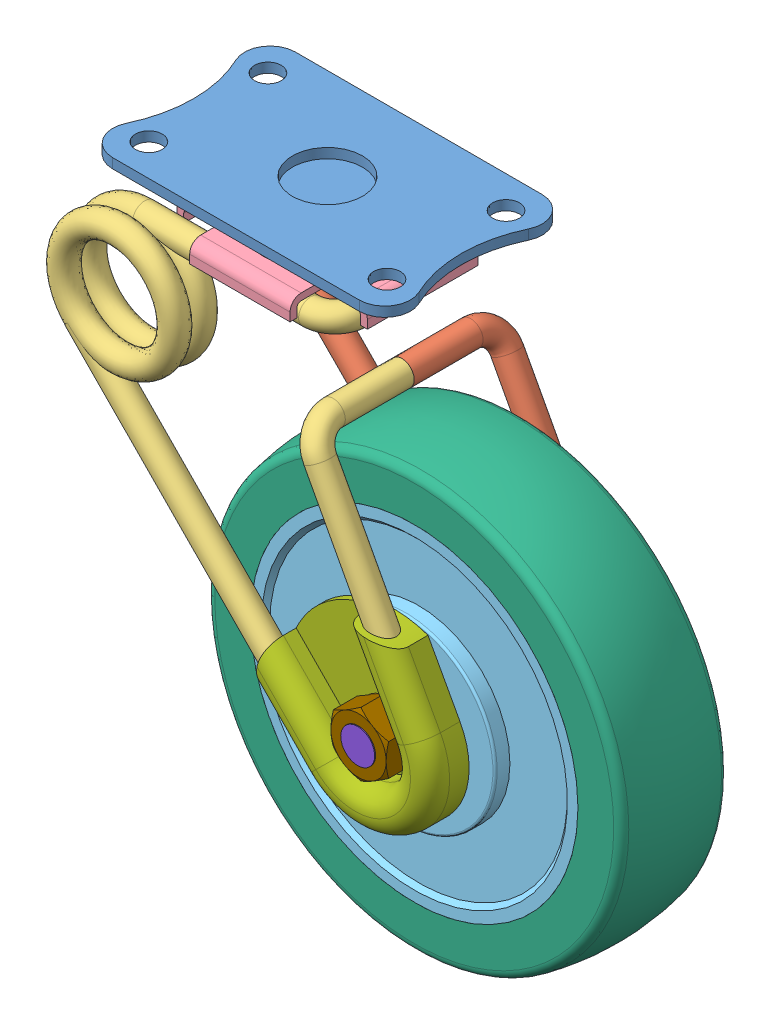
SolidWorks assembly SUSAJ-TS6-100, configuration ﾃﾞﾌｫﾙﾄ. Lengths in mm.
Overall size (125.88 136.72 53.61).
12 component instances, 9 part files, 17 mates.
Components (placement in the parent):
- table1-1: table1 [ﾃﾞﾌｫﾙﾄ] at (4.6677 7.0382 70) size (70 6.3 43)
- spring-1: spring [ﾃﾞﾌｫﾙﾄ] at (-22.2933 -17.0618 54) x (1 0 0) z (0 1 0) size (91.52 25.65 92.48)
- spring_mirror-1: spring_mirror [ﾃﾞﾌｫﾙﾄ] at (-22.2933 -17.0618 54) x (1 0 0) z (0 1 0) size (91.42 25.65 92.38)
- table2-1: table2 [ﾃﾞﾌｫﾙﾄ] at (4.6677 -4.1618 70) size (44.8 7.2 41.2)
- caster_wheel-1: caster_wheel [ﾃﾞﾌｫﾙﾄ] at (-62.4157 -78.3589 65.5546) x (0 0 -1) z (1 0 0) size (30 100 100)
  - wheel_plate-1: wheel_plate [ﾃﾞﾌｫﾙﾄ] at (-16.9454 0.9806 100) x (0 -1 0) z (0 0 1) size (77 30 77)
  - caster_tire-1: caster_tire [ﾃﾞﾌｫﾙﾄ] at (-4.4454 0.9806 100) size (25 100 100)
- cover-1: cover [ﾃﾞﾌｫﾙﾄ] at (37.5843 -77.3783 52.8) x (-1 0 0) z (0 -1 0) size (41.2 9.61 41.21)
- cover-2: cover [ﾃﾞﾌｫﾙﾄ] at (37.5843 -77.3783 87.2) x (0.28881 0.957386 0) z (0.957386 -0.28881 0) size (41.2 9.61 41.21)
- bar-1: bar [ﾃﾞﾌｫﾙﾄ] at (37.5843 -77.3783 44.2) x (1 0 0) z (0 -1 0) size (8 51.6 8)
- hexagon nut style 1_ab_jis-1: hexagon nut style 1_ab_jis [JIS B 1181 Hexagon nut - style 1 A M8 - W --N] at (37.5843 -77.3783 44.4) x (-0.923728 -0.383049 0) z (0 0 -1) size (13 15.01 6.8)
- hexagon nut style 1_ab_jis-2: hexagon nut style 1_ab_jis [JIS B 1181 Hexagon nut - style 1 A M8 - W --N] at (37.5843 -77.3783 95.6) size (13 15.01 6.8)
Mates (geometry in assembly coordinates):
- 一致1: coincident anti-aligned: plane of spring-1 through (22.4677 -4.0618 70) normal (0 0 1); plane of spring_mirror-1 through (22.4677 -4.0618 70) normal (0 0 -1)
- 一致2: coincident anti-aligned: plane of spring-1 through (22.4677 -4.0618 70) normal (0 0 1); plane of spring_mirror-1 through (22.4677 -4.0618 70) normal (0 0 -1)
- 同心円1: concentric anti-aligned: cylinder of spring-1 through (22.1801 -21.9466 78.2024) axis (0 0 -1) radius 2.9; cylinder of spring_mirror-1 through (22.1801 -21.9466 61.7976) axis (0 0 1) radius 2.9
- 同心円2: concentric anti-aligned: cylinder of spring-1 through (22.4677 -4.0618 70) axis (0 0 -1) radius 2.9; cylinder of spring_mirror-1 through (22.4677 -4.0618 70) axis (0 0 1) radius 2.9
- 一致3: coincident anti-aligned: plane of table1-1 through (4.6677 3.0382 70) normal (0 -1 0); plane of table2-1 through (4.6677 3.0382 70) normal (0 1 0)
- 同心円3: concentric anti-aligned: cylinder of table1-1 through (4.6677 7.0382 70) axis (0 1 0) radius 16; cylinder of table2-1 through (4.6677 3.0382 70) axis (0 -1 0) radius 15
- 正接3: tangent anti-aligned: cylinder of spring_mirror-1 through (16.7677 -4.0618 86) axis (-1 0 0) radius 2.9; plane of table2-1 through (4.6677 -1.1618 70) normal (0 -1 0)
- 正接4: tangent anti-aligned: cylinder of spring-1 through (16.7677 -4.0618 54) axis (-1 0 0) radius 2.9; plane of table2-1 through (4.6677 -1.1618 70) normal (0 -1 0)
- 同心円4: concentric anti-aligned: circle of spring-1; cylinder of caster_wheel-1/wheel_plate-1 through (37.5843 -77.3783 55) axis (0 0 1) radius 4
- 同心円7: concentric aligned: cylinder of caster_wheel-1/wheel_plate-1 through (37.5843 -77.3783 55) axis (0 0 1) radius 4; cylinder of cover-1 through (37.5843 -77.3783 43.6) axis (0 0 1) radius 4
- 同心円8: concentric aligned: circle of spring-1; circle of cover-1
- 同心円14: concentric anti-aligned: cylinder of caster_wheel-1/wheel_plate-1 through (37.5843 -77.3783 55) axis (0 0 1) radius 4; cylinder of bar-1 through (37.5843 -77.3783 95.8) axis (0 0 -1) radius 4
- 距離1: distance = 7 mm aligned: plane of cover-1 through (37.5843 -77.3783 51.2) normal (0 0 -1); plane of bar-1 through (37.5843 -77.3783 44.2) normal (0 0 -1)
- 同心円17: concentric anti-aligned: cylinder of bar-1 through (37.5843 -77.3783 95.8) axis (0 0 -1) radius 4; cylinder of hexagon nut style 1_ab_jis-2 through (37.5843 -77.3783 88.8) axis (0 0 1) radius 3.4
- 距離2: distance = 0.2 mm aligned: plane of hexagon nut style 1_ab_jis-2 through (24.5843 -77.3783 95.6) normal (0 0 1); plane of bar-1 through (37.5843 -77.3783 95.8) normal (0 0 1)
- 一致15: coincident anti-aligned: plane of cover-1 through (37.5843 -77.3783 51.2) normal (0 0 -1); plane of hexagon nut style 1_ab_jis-1 through (49.5927 -72.3987 51.2) normal (0 0 1)
- 同心円19: concentric aligned: cylinder of bar-1 through (37.5843 -77.3783 95.8) axis (0 0 -1) radius 4; cylinder of hexagon nut style 1_ab_jis-1 through (37.5843 -77.3783 51.2) axis (0 0 -1) radius 3.4
